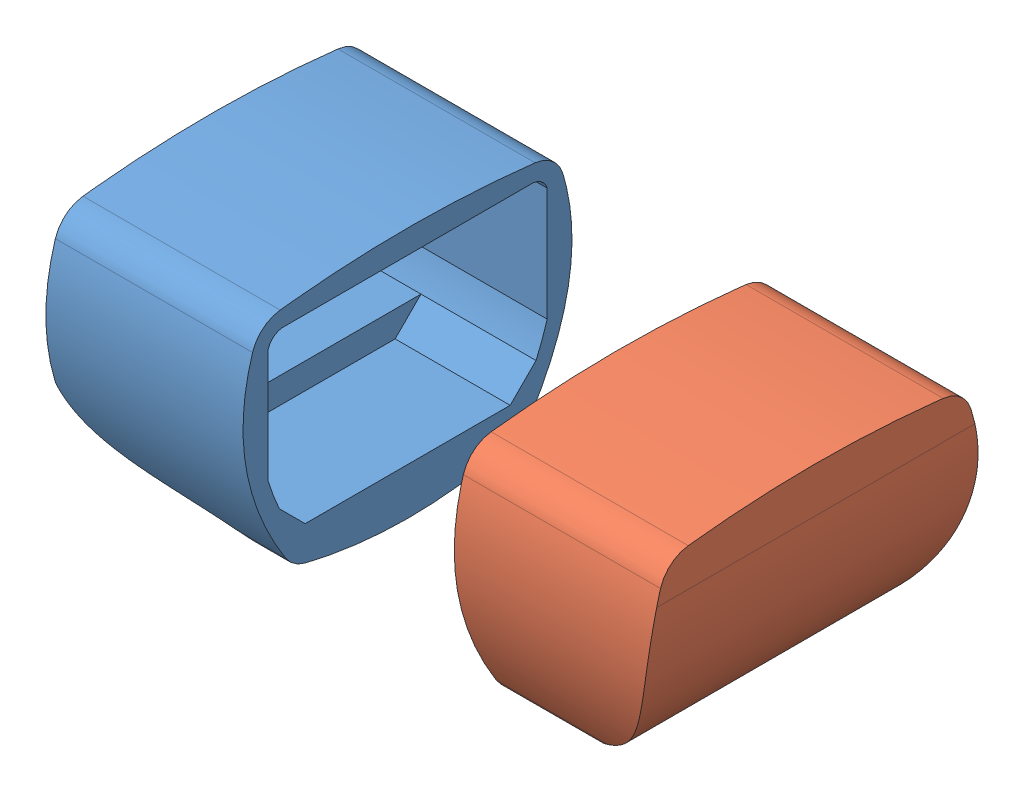
SolidWorks assembly Body_Assem, configuration Default. Lengths in mm.
Overall size (475.95 204.76 269.68).
3 component instances, 3 part files, 6 mates.
Components (placement in the parent):
- Body_back_piece-1: Body_back_piece [Default] at (-133.4703 -47.7626 29.0364) size (152.41 194.53 262.35)
- Body_center_piece-1: Body_center_piece [Default] at (36.9334 -47.7626 29.0364) size (127.02 194.53 262.35) (hidden)
- Body_front_piece-1: Body_front_piece [Default] at (334.3371 -47.7628 30.3891) x (-1 0 0) z (0 0.000212 -1) size (170.79 204.7 269.63)
Mates (geometry in assembly coordinates):
- Coincident4: coincident aligned: line of Body_back_piece-1 through (-133.4703 92.0665 128.2772) axis (1 0 0); line of Body_center_piece-1 through (36.9334 92.0665 128.2772) axis (1 0 0)
- Coincident5: coincident aligned: line of Body_back_piece-1 through (18.9297 92.0874 -68.8221) axis (-1 0 0); line of Body_center_piece-1 through (163.9334 92.0874 -68.8221) axis (-1 0 0)
- Distance2: distance = 18.0037 mm anti-aligned: plane of Body_back_piece-1 through (18.9297 3.5937 155.295) normal (1 0 0); plane of Body_center_piece-1 through (36.9334 3.5937 155.295) normal (-1 0 0)
- Distance3: distance = 18.0037 mm anti-aligned: plane of Body_center_piece-1 through (163.9334 3.5937 155.295) normal (1 0 0); plane of Body_front_piece-1 through (181.9371 3.6203 -95.8586) normal (-1 0 0)
- Coincident8: coincident aligned: line of Body_front_piece-1 through (181.9371 92.0665 128.2772) axis (1 0 0); line of Body_center_piece-1 through (36.9334 92.0665 128.2772) axis (1 0 0)
- Coincident9: coincident aligned: line of Body_center_piece-1 through (163.9334 92.0874 -68.8221) axis (-1 0 0); line of Body_front_piece-1 through (334.3371 92.0874 -68.8221) axis (-1 0 0)
